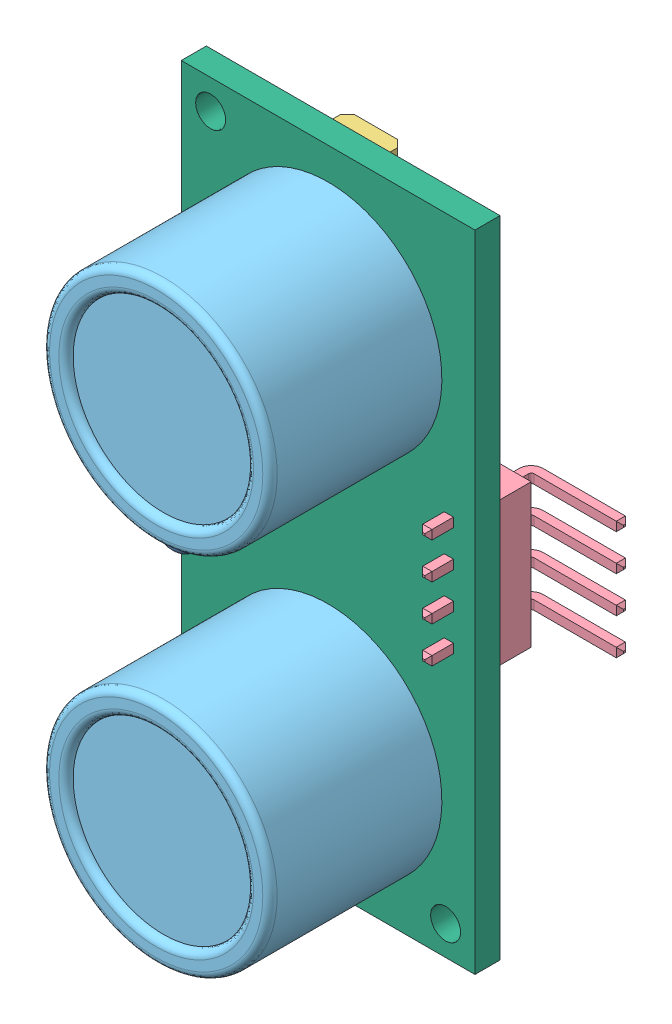
SolidWorks assembly hcSTP, configuration По умолчанию. Lengths in mm.
Overall size (639.57 1143 458.94).
14 component instances, 6 part files, 0 mates.
Components (placement in the parent):
- HC-SR04 Crystal-1: HC-SR04 Crystal [По умолчанию] at (-210.82 0 44.45) x (0 -1 0) z (0 0 1) size (254 88.9 68.58)
- Cap1 SMT-1: Cap1 SMT [По умолчанию] at (-109.093 189.926 -24.611) x (0 1 0) z (-1 0 0) size (114.3 46.84 44.45)
- Cap1 SMT-2: Cap1 SMT [По умолчанию] at (44.577 189.926 -24.611) x (0 1 0) z (-1 0 0) size (114.3 46.84 44.45)
- Cap1 SMT-3: Cap1 SMT [По умолчанию] at (109.093 189.926 -24.611) x (0 1 0) z (-1 0 0) size (114.3 46.84 44.45)
- Cap1 SMT-4: Cap1 SMT [По умолчанию] at (-173.609 189.926 -24.611) x (0 1 0) z (-1 0 0) size (114.3 46.84 44.45)
- Cap1 SMT-5: Cap1 SMT [По умолчанию] at (173.609 189.926 -24.611) x (0 1 0) z (-1 0 0) size (114.3 46.84 44.45)
- Cap1 SMT-6: Cap1 SMT [По умолчанию] at (-44.577 189.926 -24.611) x (0 1 0) z (-1 0 0) size (114.3 46.84 44.45)
- 14 Pin SMT-1: 14 Pin SMT [По умолчанию] at (0 445.196 -21.59) x (1 0 0) z (0 1 0) size (152.4 40.64 223.52)
- 14 Pin SMT-2: 14 Pin SMT [По умолчанию] at (0 -9.718 -21.59) x (1 0 0) z (0 1 0) size (152.4 40.64 223.52)
- 14 Pin SMT-3: 14 Pin SMT [По умолчанию] at (-8.89 -469.9 -21.59) x (0 -1 0) z (1 0 0) size (152.4 40.64 223.52)
- 3 Pin Header 90 Degree-1: 3 Pin Header 90 Degree [По умолчанию] at (214.0585 0 -31.75) x (-1 0 0) z (0 -1 0) size (203.26 198.59 254)
- Transducer-1: Transducer [По умолчанию] at (0 313.436 336.55) x (1 0 0) z (0 -1 0) size (403.35 304.8 403.35)
- Transducer-2: Transducer [По умолчанию] at (0 -334.264 336.55) x (1 0 0) z (0 -1 0) size (403.35 304.8 403.35)
- PCB-1: PCB [По умолчанию] at origin size (520.7 1143 44.45)
